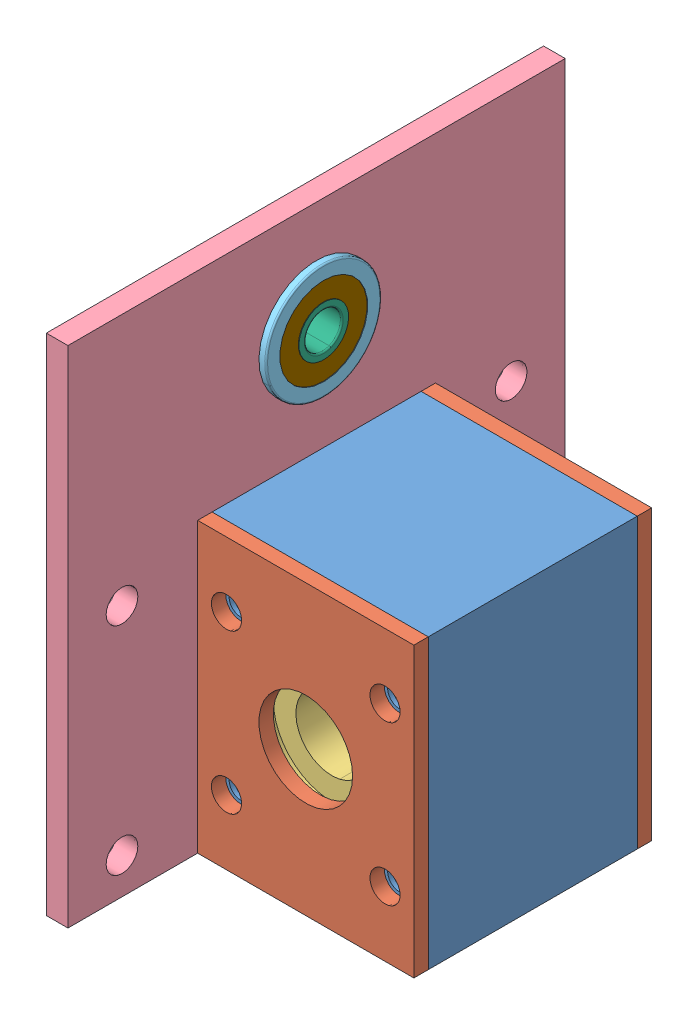
SolidWorks assembly y軸ブッシュ周辺 left, configuration ﾃﾞﾌｫﾙﾄ. Lengths in mm.
Overall size (34 70 69).
18 component instances, 9 part files, 2 mates.
Components (placement in the parent):
- yブッシュ固定-1: yブッシュ固定 [ﾃﾞﾌｫﾙﾄ] at (-4.4488 -3.141 25.6708) size (30.09 40.17 29.19)
- ブッシュ固定板-1: ブッシュ固定板 [ﾃﾞﾌｫﾙﾄ] at (-4.4488 -3.141 23.6708) size (30 40 2)
- ブッシュ固定板-2: ブッシュ固定板 [ﾃﾞﾌｫﾙﾄ] at (-4.4488 -3.141 54.6708) size (30 40 2)
- ブッシュ-1: ブッシュ [ﾃﾞﾌｫﾙﾄ] at (-2.3348 -2.6732 45.048) x (0 0 -1) z (-0.21607 0.976378 0) size (29 19 19)
- プーリー固定板 left 上-1: プーリー固定板 left 上 [ﾃﾞﾌｫﾙﾄ] at (-19.4488 -3.141 40.1708) x (0 -1 0) z (-1 0 0) size (70 69 3)
- F605ZZ-1: F605ZZ [Default] at (-23.4488 31.859 40.1708) x (1 0 0) z (0 -0.370725 0.928743) size (5 16 16)
  - _F605ZZ_Outer_Ring_2-1: _F605ZZ_Outer_Ring_2 [Default] at origin size (5 16 16)
  - _F605ZZ_Inner_Ring_4-1: _F605ZZ_Inner_Ring_4 [Default] x (1 0 0) z (0 -1 0) size (5 7.79 7.79)
  - _F605ZZ_Shield1_6-1: _F605ZZ_Shield1_6 [Default] at (0.625 0 0) x (-1 0 0) z (0 -1 0) size (0.23 12.2 12.2)
  - _F605ZZ_Ball_8-1: _F605ZZ_Ball_8 [Default] at (2.5 0 4.75) x (1 0 0) z (0 -1 0) size (2.7 2.7 2.7)
  - _F605ZZ_Ball_8-2: _F605ZZ_Ball_8 [Default] at (2.5 -3.3588 3.3588) x (1 0 0) z (0 -1 0) size (2.7 2.7 2.7)
  - _F605ZZ_Ball_8-3: _F605ZZ_Ball_8 [Default] at (2.5 -4.75 0) x (1 0 0) z (0 -1 0) size (2.7 2.7 2.7)
  - _F605ZZ_Ball_8-4: _F605ZZ_Ball_8 [Default] at (2.5 -3.3588 -3.3588) x (1 0 0) z (0 -1 0) size (2.7 2.7 2.7)
  - _F605ZZ_Ball_8-5: _F605ZZ_Ball_8 [Default] at (2.5 0 -4.75) x (1 0 0) z (0 -1 0) size (2.7 2.7 2.7)
  - _F605ZZ_Ball_8-6: _F605ZZ_Ball_8 [Default] at (2.5 3.3588 -3.3588) x (1 0 0) z (0 -1 0) size (2.7 2.7 2.7)
  - _F605ZZ_Ball_8-7: _F605ZZ_Ball_8 [Default] at (2.5 4.75 0) x (1 0 0) z (0 -1 0) size (2.7 2.7 2.7)
  - _F605ZZ_Ball_8-8: _F605ZZ_Ball_8 [Default] at (2.5 3.3588 3.3588) x (1 0 0) z (0 -1 0) size (2.7 2.7 2.7)
  - _F605ZZ_Shield2_17-1: _F605ZZ_Shield2_17 [Default] at origin size (0.23 12.2 12.2)
Mates (geometry in assembly coordinates):
- 同心円10: concentric: cylinder of プーリー固定板 left 上-1 through (-12.4488 31.859 40.1708) axis (-1 0 0) radius 7; cylinder of F605ZZ-1/_F605ZZ_Outer_Ring_2-1 through (-18.4488 31.859 40.1708) axis (-1 0 0) radius 7
- 一致4: coincident: plane of プーリー固定板 left 上-1 through (-19.4488 -3.141 40.1708) normal (1 0 0); plane of F605ZZ-1/_F605ZZ_Outer_Ring_2-1 through (-19.4488 39.2889 43.1366) normal (-1 0 0)
